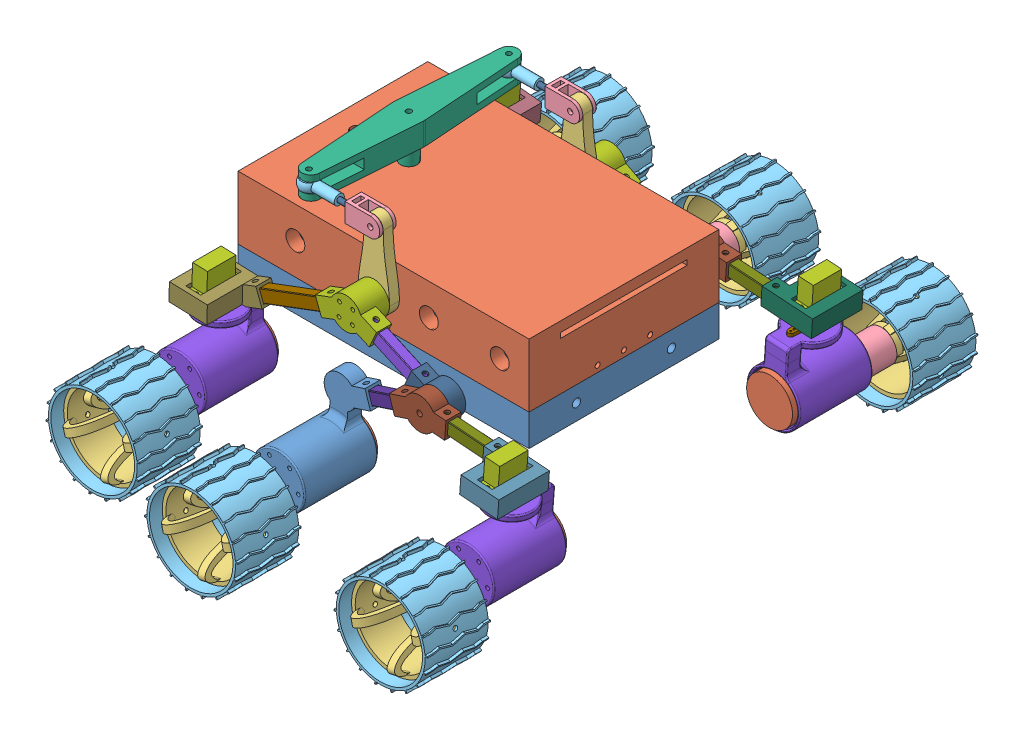
SolidWorks assembly Mars Rover Assembly, configuration Default. Lengths in mm.
Overall size (348.74 205.22 461.5).
79 component instances, 28 part files, 76 mates.
Components (placement in the parent):
- B_Base-1: B_Base [Default] at (-7.9249 156.9925 214.1068) size (230 35 150)
- T_Base-1: T_Base [Default] at (-7.9249 181.9925 214.1068) x (1 0 0) z (0 -1 0) size (230 150 50)
- A_H_Top-2: A_H_Top [Default] at (107.0751 206.9925 214.1068) x (-1 0 0) z (0 0 -1) size (25 69.5 27.75)
- A_H_Top-4: A_H_Top [Default] at (107.0751 206.9925 364.1068) size (25 69.5 27.75)
- R_B_Top-1: R_B_Top [Default] at (117.0751 266.4925 364.1068) x (0 -1 0) z (0 0 -1) size (15 27.5 13)
- R_B_Top-2: R_B_Top [Default] at (117.0751 266.4925 206.1068) x (0 -1 0) z (0 0 -1) size (15 27.5 13)
- R_E_Joint-1: R_E_Joint [Default] at (59.0751 256.4925 214.1068) x (0 0 -1) z (0 1 0) size (14 31 8)
- R_E_Joint-2: R_E_Joint [Default] at (59.0751 256.4925 372.1068) x (0 0 -1) z (0 1 0) size (14 31 8)
- R_B_Main-1: R_B_Main [Default] at (52.0751 247.4925 289.1068) size (25 33.5 170.5)
- A_H_Middle-1: A_H_Middle [Default] at (107.0751 206.9925 381.8568) x (0.999455 -0.033001 0) z (0 0 1) size (48.46 25.73 22)
- A_H_Middle-2: A_H_Middle [Default] at (107.0751 206.9925 196.3568) x (-0.995325 0.096582 0) z (0 0 -1) size (48.46 25.73 22)
- A_Back-2: A_Back [Default] at (117.4033 199.2898 391.7318) x (0.910747 -0.412964 0) z (0 0 1) size (50 9.75 7.75)
- A_Front-2: A_Front [Default] at (96.2612 199.9879 383.9818) x (-0.936005 -0.351986 0) z (0 0 -1) size (70 9.75 7.75)
- A_H_Back-1: A_H_Back [Default] at (177.3204 179.5329 381.8568) x (0.999455 -0.033001 0) z (0 0 1) size (36.73 25.73 12)
- A_H_Bottom-2: A_H_Bottom [Default] at (177.3204 179.5329 393.8568) x (0.99709 -0.076229 0) z (0 0 1) size (44.59 25.73 12)
- S_H_Front-1: S_H_Front [Default] at (16.5832 177.2364 381.8568) x (0.999455 -0.033001 0) z (0 0 1) size (45.56 18.23 40)
- S_H_Front_F-1: S_H_Front_F [Default] at (14.8719 183.0596 156.3568) x (0.995325 -0.096582 0) z (0 0 1) size (45.56 18.23 40)
- S_H_Back-1: S_H_Back [Default] at (258.6152 171.3083 393.8568) x (0.99709 -0.076229 0) z (0 0 1) size (40 14 40)
- S_H_Back_F-1: S_H_Back_F [Default] at (257.1595 169.5988 144.3568) x (0.997733 -0.067299 0) z (0 0 1) size (40 14 40)
- A_Bottom-1: A_Bottom [Default] at (187.2843 174.0073 403.7318) x (0.99709 -0.076229 0) z (0 0 1) size (50 9.75 7.75)
- A_Middle-1: A_Middle [Default] at (128.199 160.5572 403.7318) x (0.950363 0.311143 0) z (0 0 1) size (40 9.75 7.75)
- A_H_Bottom-3: A_H_Bottom [Default] at (175.4291 175.1152 184.3568) x (-0.947539 -0.31964 0) z (0 0 -1) size (44.59 25.73 12)
- A_Back-3: A_Back [Default] at (116.8918 198.6477 194.2318) x (0.8826 -0.470125 0) z (0 0 1) size (50 9.75 7.75)
- A_H_Back_F-1: A_H_Back_F [Default] at (175.4291 175.1152 184.3568) x (0.995325 -0.096582 0) z (0 0 1) size (36.73 25.73 12)
- A_Middle-2: A_Middle [Default] at (127.3379 153.8793 182.2318) x (0.947539 0.31964 0) z (0 0 1) size (40 9.75 7.75)
- A_Bottom-2: A_Bottom [Default] at (185.8074 171.6589 182.2318) x (0.997733 -0.067299 0) z (0 0 1) size (50 9.75 7.75)
- A_Front-3: A_Front [Default] at (95.8371 200.6908 186.4818) x (-0.956521 -0.291664 0) z (0 0 -1) size (70 9.75 7.75)
- Middle Wheel-1: Middle Wheel [Default] at (153.8572 132.0206 404.0875) x (0.99709 -0.076229 0) z (0 0 1) size (92.57 106.34 128.8)
  - A_H_Motor-1: A_H_Motor [Default] at (-41.8905 27.9503 -10.3557) size (45.23 74.39 57.8)
  - Motor x Wheel Assembly-1: Motor x Wheel Assembly [Default] at (18.4664 -15.3532 60.2321) x (1 0 0) z (0 0 -1) size (92.57 92.9 128.8)
    - motor-1: motor [Default] at (-60.357 -3.1473 15.5878) size (37 37 78.8)
    - wheel inner-1: wheel inner [Default] at (-60.357 3.3527 -15.4122) x (0.952401 -0.304848 0) z (0.304848 0.952401 0) size (65.75 39.75 65.75)
    - wheel x motor connector test 2-1: wheel x motor connector test 2 [Default] at (-60.357 3.3527 9.5878) x (0.889009 0.457889 0) z (0 0 -1) size (25 25 25)
    - wheel outer-1: wheel outer [Default] at (-60.357 3.3527 -55.4122) x (-0.304848 -0.952401 0) z (0 0 1) size (74.01 73.51 50)
- Middle Wheel Flipped-1: Middle Wheel Flipped [Default] at (93.5781 137.5899 168.6312) x (-0.997733 0.067299 0) z (0 0 -1) size (92.57 106.34 128.8)
  - A_H_Motor_F-1: A_H_Motor_F [Default] at (-18.4554 19.9771 -15.6006) size (45.23 74.39 57.8)
  - Motor x Wheel Assembly-1: Motor x Wheel Assembly [Default] at (41.9016 -23.3264 54.9872) x (1 0 0) z (0 0 -1) size (92.57 92.9 128.8)
    - motor-1: motor [Default] at (-60.357 -3.1473 15.5878) size (37 37 78.8)
    - wheel inner-1: wheel inner [Default] at (-60.357 3.3527 -15.4122) x (0.952401 -0.304848 0) z (0.304848 0.952401 0) size (65.75 39.75 65.75)
    - wheel x motor connector test 2-1: wheel x motor connector test 2 [Default] at (-60.357 3.3527 9.5878) x (0.889009 0.457889 0) z (0 0 -1) size (25 25 25)
    - wheel outer-1: wheel outer [Default] at (-60.357 3.3527 -55.4122) x (-0.304848 -0.952401 0) z (0 0 1) size (74.01 73.51 50)
- Servo x Wheel Assembly-1: Servo x Wheel Assembly [Default] at (235.1932 115.9485 406.1599) x (-0.001869 0.000143 0.999998) z (-0.997089 0.076229 -0.001874) size (129.25 126.15 93.2)
  - mg90s servo-1: mg90s servo [Default] at (-3.566 79.8877 -6.8981) x (0.999998 0 -0.001874) z (-0.001874 0 -0.999998) size (32.3 31.6 11.8)
  - Motor x Wheel Assembly-1: Motor x Wheel Assembly [Default] at (45.6976 3.5404 -73.377) x (-0.004847 0 -0.999988) z (-0.999988 0 0.004847) size (92.57 92.9 128.8)
    - motor-1: motor [Default] at (-60.357 -3.1473 15.5878) size (37 37 78.8)
    - wheel inner-1: wheel inner [Default] at (-60.357 3.3527 -15.4122) x (0.952401 -0.304848 0) z (0.304848 0.952401 0) size (65.75 39.75 65.75)
    - wheel x motor connector test 2-1: wheel x motor connector test 2 [Default] at (-60.357 3.3527 9.5878) x (0.889009 0.457889 0) z (0 0 -1) size (25 25 25)
    - wheel outer-1: wheel outer [Default] at (-60.357 3.3527 -55.4122) x (-0.304848 -0.952401 0) z (0 0 1) size (74.01 73.51 50)
  - servo x motor holder-1: servo x motor holder [Default] at (-15.6769 41.6877 -12.7219) x (0.999988 0 -0.004847) z (0.004847 0 0.999988) size (57.8 61 42)
  - mg90s servo horn-1: mg90s servo horn [Default] at (20.3227 46.6877 -12.8964) x (-0.999988 0 0.004847) z (-0.004847 0 -0.999988) size (36 5 19)
- Servo x Wheel Assembly-2: Servo x Wheel Assembly [Default] at (15.8137 125.7164 184.0537) x (0.001866 -0.000181 -0.999998) z (0.995323 -0.096582 0.001874) size (129.25 126.15 93.2)
  - mg90s servo-1: mg90s servo [Default] at (-3.566 79.8877 -6.8981) x (0.999998 0 -0.001874) z (-0.001874 0 -0.999998) size (32.3 31.6 11.8)
  - Motor x Wheel Assembly-1: Motor x Wheel Assembly [Default] at (45.6976 3.5404 -73.377) x (-0.004847 0 -0.999988) z (-0.999988 0 0.004847) size (92.57 92.9 128.8)
    - motor-1: motor [Default] at (-60.357 -3.1473 15.5878) size (37 37 78.8)
    - wheel inner-1: wheel inner [Default] at (-60.357 3.3527 -15.4122) x (0.952401 -0.304848 0) z (0.304848 0.952401 0) size (65.75 39.75 65.75)
    - wheel x motor connector test 2-1: wheel x motor connector test 2 [Default] at (-60.357 3.3527 9.5878) x (0.889009 0.457889 0) z (0 0 -1) size (25 25 25)
    - wheel outer-1: wheel outer [Default] at (-60.357 3.3527 -55.4122) x (-0.304848 -0.952401 0) z (0 0 1) size (74.01 73.51 50)
  - servo x motor holder-1: servo x motor holder [Default] at (-15.6769 41.6877 -12.7219) x (0.999988 0 -0.004847) z (0.004847 0 0.999988) size (57.8 61 42)
  - mg90s servo horn-1: mg90s servo horn [Default] at (20.3227 46.6877 -12.8964) x (-0.999988 0 0.004847) z (-0.004847 0 -0.999988) size (36 5 19)
- Servo x Wheel Assembly-3: Servo x Wheel Assembly [Default] at (259.7856 112.308 172.0537) x (0.00187 -0.000126 -0.999998) z (0.997731 -0.067299 0.001874) size (129.25 126.15 93.2)
  - mg90s servo-1: mg90s servo [Default] at (-3.566 79.8877 -6.8981) x (0.999998 0 -0.001874) z (-0.001874 0 -0.999998) size (32.3 31.6 11.8)
  - Motor x Wheel Assembly-1: Motor x Wheel Assembly [Default] at (45.6976 3.5404 -73.377) x (-0.004847 0 -0.999988) z (-0.999988 0 0.004847) size (92.57 92.9 128.8)
    - motor-1: motor [Default] at (-60.357 -3.1473 15.5878) size (37 37 78.8)
    - wheel inner-1: wheel inner [Default] at (-60.357 3.3527 -15.4122) x (0.952401 -0.304848 0) z (0.304848 0.952401 0) size (65.75 39.75 65.75)
    - wheel x motor connector test 2-1: wheel x motor connector test 2 [Default] at (-60.357 3.3527 9.5878) x (0.889009 0.457889 0) z (0 0 -1) size (25 25 25)
    - wheel outer-1: wheel outer [Default] at (-60.357 3.3527 -55.4122) x (-0.304848 -0.952401 0) z (0 0 1) size (74.01 73.51 50)
  - servo x motor holder-1: servo x motor holder [Default] at (-15.6769 41.6877 -12.7219) x (0.999988 0 -0.004847) z (0.004847 0 0.999988) size (57.8 61 42)
  - mg90s servo horn-1: mg90s servo horn [Default] at (20.3227 46.6877 -12.8964) x (-0.999988 0 0.004847) z (-0.004847 0 -0.999988) size (36 5 19)
- Servo x Wheel Assembly-4: Servo x Wheel Assembly [Default] at (-4.4208 120.9147 394.1599) x (-0.001873 0.000062 0.999998) z (-0.999454 0.033001 -0.001874) size (129.25 126.15 93.2)
  - mg90s servo-1: mg90s servo [Default] at (-3.566 79.8877 -6.8981) x (0.999998 0 -0.001874) z (-0.001874 0 -0.999998) size (32.3 31.6 11.8)
  - Motor x Wheel Assembly-1: Motor x Wheel Assembly [Default] at (45.6976 3.5404 -73.377) x (-0.004847 0 -0.999988) z (-0.999988 0 0.004847) size (92.57 92.9 128.8)
    - motor-1: motor [Default] at (-60.357 -3.1473 15.5878) size (37 37 78.8)
    - wheel inner-1: wheel inner [Default] at (-60.357 3.3527 -15.4122) x (0.952401 -0.304848 0) z (0.304848 0.952401 0) size (65.75 39.75 65.75)
    - wheel x motor connector test 2-1: wheel x motor connector test 2 [Default] at (-60.357 3.3527 9.5878) x (0.889009 0.457889 0) z (0 0 -1) size (25 25 25)
    - wheel outer-1: wheel outer [Default] at (-60.357 3.3527 -55.4122) x (-0.304848 -0.952401 0) z (0 0 1) size (74.01 73.51 50)
  - servo x motor holder-1: servo x motor holder [Default] at (-15.6769 41.6877 -12.7219) x (0.999988 0 -0.004847) z (0.004847 0 0.999988) size (57.8 61 42)
  - mg90s servo horn-1: mg90s servo horn [Default] at (20.3227 46.6877 -12.8964) x (-0.999988 0 0.004847) z (-0.004847 0 -0.999988) size (36 5 19)
- ROD-1: ROD [Default] at (87.0751 256.4925 368.1068) x (0 0.904681 0.426089) z (0 -0.426089 0.904681) size (4 11 4)
- ROD-2: ROD [Default] at (87.0751 256.4925 210.1068) x (0 1 0) z (0 0 1) size (4 11 4)
Mates (geometry in assembly coordinates):
- Coincident2: coincident: point of B_Base-1; point of T_Base-1
- Coincident5: coincident anti-aligned: plane of B_Base-1 through (-7.9249 181.9925 364.1068) normal (0 1 0); plane of T_Base-1 through (-7.9249 181.9925 364.1068) normal (0 -1 0)
- Coincident6: coincident: point of B_Base-1; point of T_Base-1
- Coincident35: coincident anti-aligned: circle of T_Base-1; circle of R_B_Main-1
- Coincident49: coincident anti-aligned: plane of A_H_Middle-1 through (92.9111 209.1447 391.8568) normal (0.351986 -0.936005 0); plane of A_Front-2 through (27.309 184.475 383.9818) normal (-0.351986 0.936005 0)
- Coincident53: coincident anti-aligned: circle of A_H_Middle-1; circle of A_Front-2
- Parallel10: parallel anti-aligned: plane of A_H_Middle-1 through (92.9111 209.1447 383.8568) normal (0 0 1); plane of A_Front-2 through (30.7409 175.3489 383.9818) normal (0 0 -1)
- Coincident55: coincident anti-aligned: plane of A_H_Middle-1 through (121.3502 208.2057 391.8568) normal (-0.412964 -0.910747 0); plane of A_Back-2 through (166.9671 187.5214 391.7318) normal (0.412964 0.910747 0)
- Coincident56: coincident aligned: circle of A_H_Middle-1; circle of A_Back-2
- Parallel11: parallel anti-aligned: plane of A_H_Middle-1 through (121.3502 208.2057 383.8568) normal (0 0 1); plane of A_Back-2 through (162.9407 178.6416 383.9818) normal (0 0 -1)
- Coincident58: coincident anti-aligned: plane of A_Back-2 through (166.9671 187.5214 391.7318) normal (0.412964 0.910747 0); plane of A_H_Back-1 through (167.175 187.4272 383.8568) normal (-0.412964 -0.910747 0)
- Coincident59: coincident aligned: circle of A_Back-2; circle of A_H_Back-1
- Parallel12: parallel anti-aligned: plane of A_Back-2 through (162.9407 178.6416 383.9818) normal (0 0 -1); plane of A_H_Back-1 through (167.175 187.4272 383.8568) normal (0 0 1)
- Coincident66: coincident anti-aligned: plane of T_Base-1 through (-7.9249 181.9925 364.1068) normal (0 0 1); plane of A_H_Top-4 through (117.0751 229.0424 364.1068) normal (0 0 -1)
- Concentric7: concentric anti-aligned: circle of A_H_Back-1; circle of A_H_Bottom-2
- Coincident67: coincident anti-aligned: plane of A_H_Back-1 through (177.3204 179.5329 393.8568) normal (0 0 1); plane of A_H_Bottom-2 through (177.3204 179.5329 393.8568) normal (0 0 -1)
- Concentric8: concentric aligned: circle of R_E_Joint-2; circle of R_B_Main-1
- Concentric9: concentric aligned: circle of R_E_Joint-1; circle of R_B_Main-1
- Coincident76: coincident aligned: circle of A_Front-2; circle of S_H_Front-1
- Parallel13: parallel anti-aligned: plane of A_Front-2 through (30.7409 175.3489 391.7318) normal (0 0 1); plane of S_H_Front-1 through (27.2273 184.4442 391.8568) normal (0 0 -1)
- Coincident87: coincident aligned: circle of A_H_Bottom-2; circle of A_Bottom-1
- Parallel14: parallel anti-aligned: plane of A_H_Bottom-2 through (188.0276 183.7289 403.8568) normal (0 0 -1); plane of A_Bottom-1 through (237.1388 170.1958 403.7318) normal (0 0 1)
- Coincident89: coincident aligned: circle of S_H_Back-1; circle of A_Bottom-1
- Parallel15: parallel anti-aligned: plane of S_H_Back-1 through (237.8821 179.9174 395.8568) normal (0 0 1); plane of A_Bottom-1 through (237.1388 170.1958 395.9818) normal (0 0 -1)
- Coincident92: coincident aligned: circle of A_H_Bottom-2; circle of A_Middle-1
- Parallel16: parallel anti-aligned: plane of A_H_Bottom-2 through (163.2629 182.2961 395.8568) normal (0 0 1); plane of A_Middle-1 through (166.2135 173.0029 395.9818) normal (0 0 -1)
- Coincident95: coincident anti-aligned: circle of A_H_Middle-2; circle of A_Back-3
- Parallel18: parallel anti-aligned: plane of A_H_Middle-2 through (121.3985 207.2942 194.3568) normal (0 0 -1); plane of A_Back-3 through (161.0218 175.1415 194.2318) normal (0 0 1)
- Coincident97: coincident anti-aligned: plane of T_Base-1 through (-7.9249 181.9925 214.1068) normal (0 0 -1); plane of A_H_Top-2 through (97.0751 229.0424 214.1068) normal (0 0 1)
- Coincident98: coincident aligned: circle of A_Back-3; circle of A_H_Back_F-1
- Parallel19: parallel anti-aligned: plane of A_Back-3 through (161.0218 175.1415 186.4818) normal (0 0 -1); plane of A_H_Back_F-1 through (165.807 183.6396 186.3568) normal (0 0 1)
- Coincident100: coincident anti-aligned: plane of A_H_Bottom-3 through (175.4291 175.1152 184.3568) normal (0 0 1); plane of A_H_Back_F-1 through (175.4291 175.1152 184.3568) normal (0 0 -1)
- Concentric18: concentric anti-aligned: circle of A_H_Bottom-3; circle of A_H_Back_F-1
- Coincident101: coincident aligned: circle of A_H_Bottom-3; circle of A_Middle-2
- Parallel20: parallel anti-aligned: plane of A_H_Bottom-3 through (164.018 176.5427 174.3568) normal (0 0 1); plane of A_Middle-2 through (165.2395 166.6649 174.4818) normal (0 0 -1)
- Coincident103: coincident aligned: circle of A_H_Bottom-3; circle of A_Bottom-2
- Parallel21: parallel anti-aligned: plane of A_H_Bottom-3 through (188.3719 181.2581 182.3568) normal (0 0 -1); plane of A_Bottom-2 through (235.694 168.294 182.2318) normal (0 0 1)
- Coincident105: coincident aligned: circle of S_H_Back_F-1; circle of A_Bottom-2
- Parallel22: parallel anti-aligned: plane of S_H_Back_F-1 through (236.3502 178.0219 174.3568) normal (0 0 1); plane of A_Bottom-2 through (235.694 168.294 174.4818) normal (0 0 -1)
- Concentric19: concentric aligned: circle of A_H_Top-4; circle of R_B_Top-1
- Concentric20: concentric anti-aligned: circle of A_H_Top-2; circle of R_B_Top-2
- Coincident112: coincident anti-aligned: plane of A_H_Top-2 through (97.0751 229.0424 214.1068) normal (0 0 1); plane of R_B_Top-2 through (107.0751 256.4925 214.1068) normal (0 0 -1)
- Perpendicular1: perpendicular: line of A_H_Top-4 through (107.0751 194.4925 364.1068) axis (0 1 0); line of R_B_Top-1 through (87.0751 256.4925 361.6068) axis (1 0 0)
- Perpendicular2: perpendicular: line of T_Base-1 through (222.0751 231.9925 364.1068) axis (-1 0 0); line of A_H_Top-4 through (107.0751 194.4925 364.1068) axis (0 1 0)
- Concentric22: concentric aligned: circle of A_H_Top-4; circle of A_H_Middle-1
- Coincident113: coincident anti-aligned: circle of S_H_Front_F-1; circle of A_Front-3
- Coincident117: coincident aligned: circle of A_H_Middle-2; circle of A_Front-3
- Parallel24: parallel anti-aligned: plane of A_H_Middle-2 through (93.0769 210.0424 186.3568) normal (0 0 1); plane of A_Front-3 through (28.8807 180.2743 186.4818) normal (0 0 -1)
- Coincident145: coincident anti-aligned: plane of A_H_Top-4 through (107.0751 206.9925 391.8568) normal (0 0 1); plane of A_H_Middle-1 through (107.0751 206.9925 391.8568) normal (0 0 -1)
- Coincident153: coincident anti-aligned: plane of A_H_Top-2 through (107.0751 206.9925 186.3568) normal (0 0 -1); plane of A_H_Middle-2 through (107.0751 206.9925 186.3568) normal (0 0 1)
- Concentric35: concentric aligned: cylinder of A_H_Top-2 through (107.0751 206.9925 186.3568) axis (0 0 1) radius 11; cylinder of A_H_Middle-2 through (107.0751 206.9925 186.3568) axis (0 0 1) radius 11.25
- Parallel25: parallel anti-aligned: plane of S_H_Front_F-1 through (28.87 180.0097 186.3568) normal (0 0 1); plane of A_Front-3 through (28.8807 180.2743 186.4818) normal (0 0 -1)
- Coincident187: coincident anti-aligned: plane of A_Middle-1 through (128.199 160.5572 403.7318) normal (-0.950363 -0.311143 0); plane of Middle Wheel-1/A_H_Motor-1 through (126.0988 166.9721 393.7318) normal (0.950363 0.311143 0)
- Coincident188: coincident anti-aligned: plane of A_Middle-1 through (166.2135 173.0029 403.7318) normal (0 0 1); plane of Middle Wheel-1/A_H_Motor-1 through (125.1653 169.8232 403.7318) normal (0 0 -1)
- Coincident189: coincident anti-aligned: plane of A_Middle-1 through (163.1799 182.269 403.7318) normal (-0.311143 0.950363 0); plane of Middle Wheel-1/A_H_Motor-1 through (125.1653 169.8232 403.7318) normal (0.311143 -0.950363 0)
- Coincident191: coincident anti-aligned: plane of A_Middle-2 through (127.3379 153.8793 182.2318) normal (-0.947539 -0.31964 0); plane of Middle Wheel Flipped-1/A_H_Motor_F-1 through (125.1803 160.2752 184.2318) normal (0.947539 0.31964 0)
- Coincident192: coincident anti-aligned: plane of A_Middle-2 through (165.2395 166.6649 182.2318) normal (0 0 1); plane of Middle Wheel Flipped-1/A_H_Motor_F-1 through (124.2214 163.1178 182.2318) normal (0 0 -1)
- Coincident193: coincident anti-aligned: plane of A_Middle-2 through (162.123 175.9034 182.2318) normal (-0.31964 0.947539 0); plane of Middle Wheel Flipped-1/A_H_Motor_F-1 through (124.2214 163.1178 182.2318) normal (0.31964 -0.947539 0)
- Coincident194: coincident anti-aligned: circle of S_H_Back-1; circle of Servo x Wheel Assembly-1/mg90s servo-1
- Coincident195: coincident anti-aligned: circle of S_H_Back-1; circle of Servo x Wheel Assembly-1/mg90s servo-1
- Coincident197: coincident anti-aligned: circle of S_H_Back_F-1; circle of Servo x Wheel Assembly-3/mg90s servo-1
- Coincident198: coincident anti-aligned: circle of S_H_Back_F-1; circle of Servo x Wheel Assembly-3/mg90s servo-1
- Coincident199: coincident anti-aligned: circle of S_H_Front_F-1; circle of Servo x Wheel Assembly-2/mg90s servo-1
- Coincident200: coincident anti-aligned: circle of S_H_Front_F-1; circle of Servo x Wheel Assembly-2/mg90s servo-1
- Coincident201: coincident anti-aligned: circle of S_H_Front-1; circle of Servo x Wheel Assembly-4/mg90s servo-1
- Coincident202: coincident anti-aligned: circle of S_H_Front-1; circle of Servo x Wheel Assembly-4/mg90s servo-1
- Perpendicular3: perpendicular: line of T_Base-1 through (222.0751 231.9925 214.1068) axis (-1 0 0); line of A_H_Top-2 through (107.0751 194.4925 214.1068) axis (0 1 0)
- Perpendicular4: perpendicular: line of A_H_Top-2 through (107.0751 194.4925 214.1068) axis (0 1 0); line of R_B_Top-2 through (87.0751 256.4925 203.6068) axis (1 0 0)
- Coincident205: coincident anti-aligned: circle of R_E_Joint-2; plane of ROD-1 through (76.0751 256.4925 368.1068) normal (-1 0 0)
- Coincident206: coincident anti-aligned: circle of R_E_Joint-2; circle of ROD-1
- Coincident207: coincident aligned: plane of R_B_Top-1 through (87.0751 263.9925 361.6068) normal (-1 0 0); circle of ROD-1
- Coincident208: coincident aligned: plane of A_H_Top-4 through (117.0751 229.0424 364.1068) normal (0 0 -1); circle of R_B_Top-1
- Coincident209: coincident aligned: circle of R_B_Top-1; circle of ROD-1
- Coincident210: coincident anti-aligned: circle of R_E_Joint-1; plane of ROD-2 through (76.0751 256.4925 210.1068) normal (-1 0 0)
- Coincident211: coincident anti-aligned: circle of R_E_Joint-1; circle of ROD-2
- Coincident217: coincident aligned: circle of R_B_Top-2; circle of ROD-2
